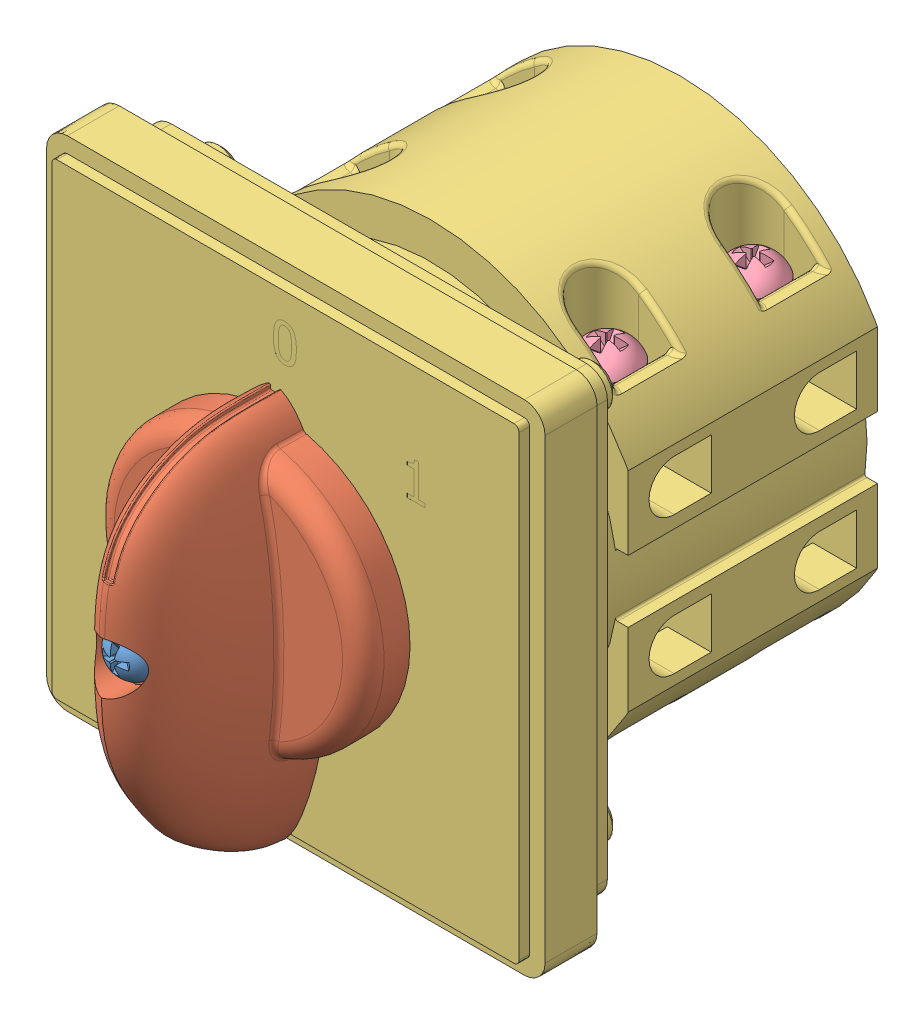
SolidWorks assembly SPR-V1 5000.00-A Rotary Switch, configuration Default. Lengths in mm.
Overall size (48 48 55.77).
12 component instances, 4 part files, 0 mates.
Components (placement in the parent):
- Iek ПКП - 10 0_1.stp-1: Iek ПКП - 10 0_1.stp [Default] at origin size (48 48 55.77)
  - Винт A2 ГОСТ 17473-80 M2.5-6gx10.stp-1: Винт A2 ГОСТ 17473-80 M2.5-6gx10.stp [Default] at (30.8608 -1.5859 79.2261) x (1 0 0) z (0 -1 0) size (4.5 11.67 4.5)
  - Iek ПКП - 10 0_1.stp-1: Iek ПКП - 10 0_1.stp [Default] at (30.8608 -1.5859 65.2261) x (-1 0 0) z (0 0 -1) size (26 38.02 16.92)
  - Корпус.stp-1: Корпус.stp [Default] at (30.8608 -1.5859 58.2261) size (48 48 40)
  - Винт A2 ГОСТ 17473-80 M3-6gx4.stp-1: Винт A2 ГОСТ 17473-80 M3-6gx4.stp [Default] at (18.8608 11.6141 45.2261) x (0.986395 0 0.164394) z (-0.164394 0 0.986395) size (5.5 6.06 5.5)
  - Винт A2 ГОСТ 17473-80 M3-6gx4.stp-2: Винт A2 ГОСТ 17473-80 M3-6gx4.stp [Default] at (18.8608 11.6141 31.2261) x (0.986395 0 0.164394) z (-0.164394 0 0.986395) size (5.5 6.06 5.5)
  - Винт A2 ГОСТ 17473-80 M3-6gx4.stp-3: Винт A2 ГОСТ 17473-80 M3-6gx4.stp [Default] at (42.8608 -14.7859 45.2261) x (-0.986395 0 0.164394) z (0.164394 0 0.986395) size (5.5 6.06 5.5)
  - Винт A2 ГОСТ 17473-80 M3-6gx4.stp-4: Винт A2 ГОСТ 17473-80 M3-6gx4.stp [Default] at (42.8608 -14.7859 31.2261) x (-0.986395 0 0.164394) z (0.164394 0 0.986395) size (5.5 6.06 5.5)
  - Винт A2 ГОСТ 17473-80 M3-6gx4.stp-5: Винт A2 ГОСТ 17473-80 M3-6gx4.stp [Default] at (42.8608 11.6141 31.2261) x (0.986395 0 -0.164394) z (0.164394 0 0.986395) size (5.5 6.06 5.5)
  - Винт A2 ГОСТ 17473-80 M3-6gx4.stp-6: Винт A2 ГОСТ 17473-80 M3-6gx4.stp [Default] at (42.8608 11.6141 45.2261) x (0.986395 0 -0.164394) z (0.164394 0 0.986395) size (5.5 6.06 5.5)
  - Винт A2 ГОСТ 17473-80 M3-6gx4.stp-7: Винт A2 ГОСТ 17473-80 M3-6gx4.stp [Default] at (18.8608 -14.7859 31.2261) x (-0.986395 0 -0.164394) z (-0.164394 0 0.986395) size (5.5 6.06 5.5)
  - Винт A2 ГОСТ 17473-80 M3-6gx4.stp-8: Винт A2 ГОСТ 17473-80 M3-6gx4.stp [Default] at (18.8608 -14.7859 45.2261) x (-0.986395 0 -0.164394) z (-0.164394 0 0.986395) size (5.5 6.06 5.5)
